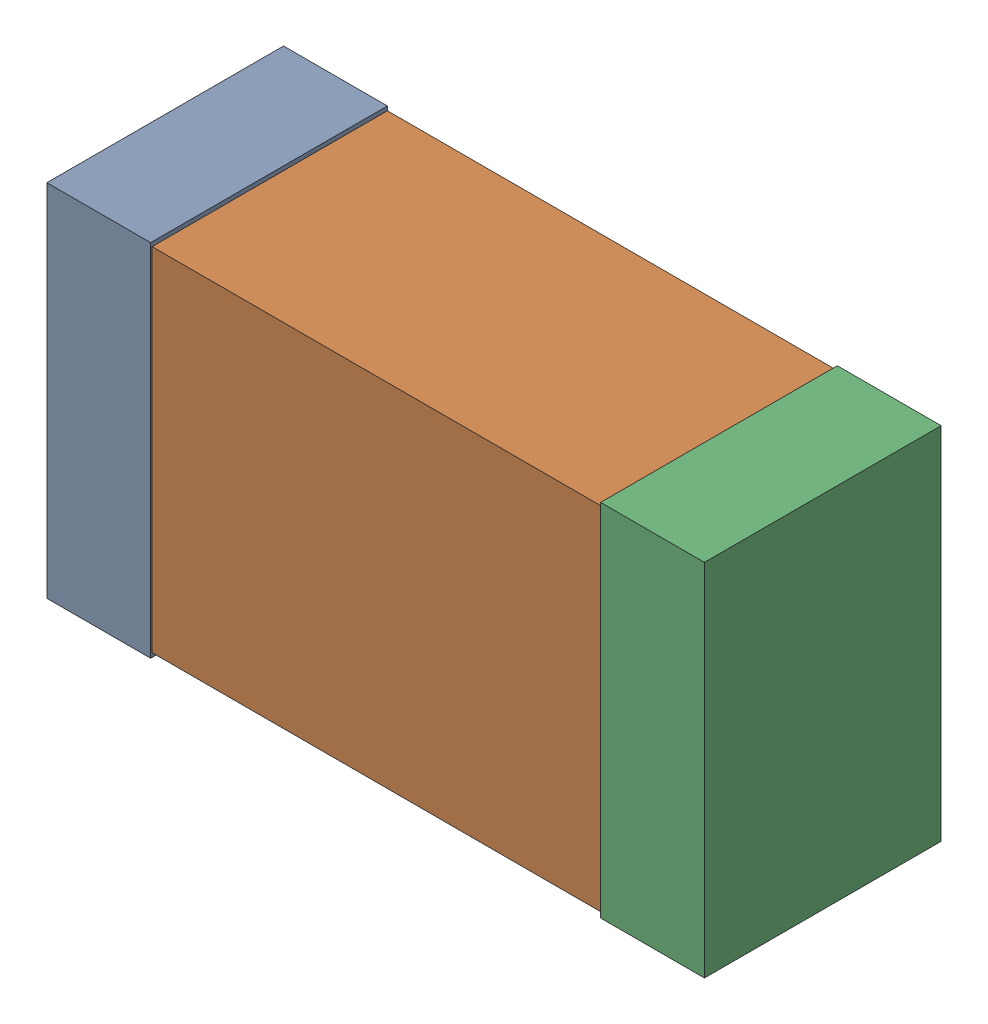
SolidWorks assembly C2Kanaloa_v2.0.0_Power, configuration Default. Lengths in mm.
Overall size (2.38 1.3 0.85).
6 component instances, 2 part files, 0 mates.
Components (placement in the parent):
- 352877648-1: 352877648 [Default] at (82.225 117.45 0) size (0.38 1.3 0.85)
  - Extruded_14-1: Extruded_14 [Default] at origin size (0.38 1.3 0.85)
- 352877904-1: 352877904 [Default] at (83.225 117.45 0) size (2.2 1.27 0.85)
  - Extruded_18-1: Extruded_18 [Default] at origin size (2.2 1.27 0.85)
- 352877648-2: 352877648 [Default] at (84.225 117.45 0) size (0.38 1.3 0.85)
  - Extruded_14-1: Extruded_14 [Default] at origin size (0.38 1.3 0.85)
